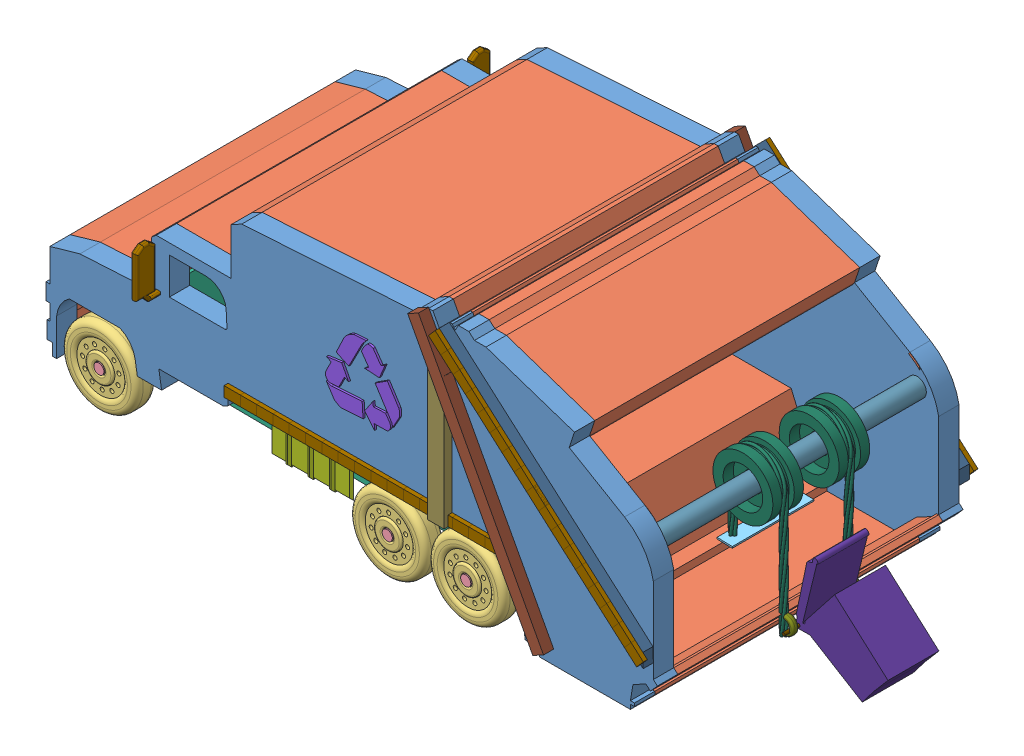
SolidWorks assembly Tech Fair Recycling Truck Final Assembly, configuration Default. Lengths in mm.
Overall size (91.31 33.89 44.17).
62 component instances, 31 part files, 112 mates.
Components (placement in the parent):
- Recycling Truck Side Panel-1: Recycling Truck Side Panel [Default] at (-47.2154 -27.4491 1.0648) size (76.2 30.73 2.54)
- Recycling Truck Side Panel-3: Recycling Truck Side Panel [Default] at (-47.2154 -27.4491 -34.4952) size (76.2 30.73 2.54)
- Part2^Tech Fair Recycling Truck Final Assembly-1: Part2^Tech Fair Recycling Truck Final Assembly [Default] at (-47.2154 -27.4491 1.0648) x (-1 0 0) z (0 0 -1) size (76.2 30.73 33.02) (virtual)
- Wheel-1: Wheel [Default] at (-36.0325 -11.6422 1.0648) x (0.936183 0.351512 0) z (0 0 1) size (9.53 9.53 2.54)
- Wheel-2: Wheel [Default] at (-36.0325 -11.6422 -34.4952) size (9.53 9.53 2.54)
- Front Wheel Axle-1: Front Wheel Axle [Default] at (-36.0325 -11.6422 -34.4952) size (1.27 1.27 38.1)
- Wheel Mounting Mechanism-3: Wheel Mounting Mechanism [Default] at (-41.5697 -12.5312 -14.1752) size (58.17 1.78 2.54)
- Front Wheel Axle-2: Front Wheel Axle [Default] at (-0.0915 -11.6422 -34.4952) x (0.996985 0.077595 0) z (0 0 1) size (1.27 1.27 38.1)
- Front Wheel Axle-3: Front Wheel Axle [Default] at (9.6875 -11.6422 -34.4952) x (-0.493037 -0.870008 0) z (0 0 1) size (1.27 1.27 38.1)
- Wheel-3: Wheel [Default] at (-0.0915 -11.6422 -34.4952) x (0.607478 -0.794336 0) z (0 0 1) size (9.53 9.53 2.54)
- Wheel-4: Wheel [Default] at (-0.0915 -11.6422 1.0648) x (0.999476 0.032368 0) z (0 0 1) size (9.53 9.53 2.54)
- Wheel-5: Wheel [Default] at (9.6875 -11.6422 -34.4952) x (-0.940272 -0.340425 0) z (0 0 1) size (9.53 9.53 2.54)
- Wheel-6: Wheel [Default] at (9.6875 -11.6422 1.0648) x (-0.248022 0.968754 0) z (0 0 1) size (9.53 9.53 2.54)
- Part Behind Wheels-1: Part Behind Wheels [Default] at (-20.0352 -6.4054 -1.7292) size (44.86 4.12 2.54)
- part on top of part behind wheels-1: part on top of part behind wheels [Default] at (-16.999 -12.5136 0.8108) size (10.16 5.08 0.76)
- Part Behind Wheels-2: Part Behind Wheels [Default] at (-19.9803 -6.4054 -31.7012) size (44.86 4.12 2.54)
- part on top of part behind wheels-4: part on top of part behind wheels [Default] at (-6.7184 -12.0011 -31.7012) x (-1 0 0) z (0 0 -1) size (10.16 5.08 0.76)
- Part3^Tech Fair Recycling Truck Final Assembly-1: Part3^Tech Fair Recycling Truck Final Assembly [Default] at origin (virtual)
- Part4^Tech Fair Recycling Truck Final Assembly-1: Part4^Tech Fair Recycling Truck Final Assembly [Default] at origin (virtual)
- Part6^Tech Fair Recycling Truck Final Assembly-1: Part6^Tech Fair Recycling Truck Final Assembly [Default] at origin (virtual)
- Recycyling Logo-1: Recycyling Logo [Default] at (-9.4381 -4.108 -34.7492) x (0.997898 0.064811 0) z (0 0 1) size (9.26 9.23 0.25)
- Recycyling Logo-2: Recycyling Logo [Default] at (-8.8451 -4.0695 3.6048) x (0.997898 0.064811 0) z (0 0 1) size (9.26 9.23 0.25)
- Color Part on top of side panel-1: Color Part on top of side panel [Default] at (-19.9264 -6.4054 3.6048) size (18.29 1.27 0.51)
- Color Part on top of side panel-2: Color Part on top of side panel [Default] at (-3.6704 -6.4054 3.6048) size (18.29 1.27 0.51)
- Color Part on top of side panel-3: Color Part on top of side panel [Default] at (-19.9264 -6.4054 -35.0032) size (18.29 1.27 0.51)
- Color Part on top of side panel-4: Color Part on top of side panel [Default] at (-3.6704 -6.4054 -35.0032) size (18.29 1.27 0.51)
- Side Part on Back-1: Side Part on Back [Default] at (6.8086 14.2643 3.6048) x (0.751135 -0.660149 0) z (0 0 1) size (36.83 1.27 1.27)
- Side Part on Back-2: Side Part on Back [Default] at (6.8698 14.334 -35.7652) x (0.751135 -0.660149 0) z (0 0 1) size (36.83 1.27 1.27)
- Color Part on top of side panel-5: Color Part on top of side panel [Default] at (6.819 14.2761 4.8748) x (0.751135 -0.660149 0) z (0 0 1) size (18.29 1.27 0.51)
- Color Part on top of side panel-6: Color Part on top of side panel [Default] at (19.0295 3.5448 4.8748) x (0.751135 -0.660149 0) z (0 0 1) size (18.29 1.27 0.51)
- Color Part on top of side panel-7: Color Part on top of side panel [Default] at (19.0803 3.6026 -36.2732) x (0.751135 -0.660149 0) z (0 0 1) size (18.29 1.27 0.51)
- Color Part on top of side panel-8: Color Part on top of side panel [Default] at (6.8698 14.334 -36.2732) x (0.751135 -0.660149 0) z (0 0 1) size (18.29 1.27 0.51)
- New Part-3: New Part [Default] at (3.7219 14.8477 3.6048) x (0.472165 -0.88151 0) z (0 0 1) size (33.02 1.52 1.27)
- Bar-1: Bar [Default] at (5.9675 10.1046 3.6048) size (2.03 16.51 1.02)
- New Part-2: New Part [Default] at (3.8237 14.7802 -35.7652) x (0.472165 -0.88151 0) z (0 0 1) size (33.02 1.52 1.27)
- Bar-2: Bar [Default] at (6.0879 10.1046 -35.5112) size (2.03 16.51 1.02)
- Gas Tank-1: Gas Tank [Default] at (-25.9449 -8.4074 -5.5392) size (15.24 6.76 7.62)
- Gas Tank-2: Gas Tank [Default] at (-25.9449 -8.4074 -17.7312) size (15.24 6.76 7.62)
- Part7^Tech Fair Recycling Truck Final Assembly-1: Part7^Tech Fair Recycling Truck Final Assembly [Default] at origin (virtual)
- Mount for Pulley-1: Mount for Pulley [Default] at (30.3925 1.8436 -31.9552) size (2.29 2.29 33.02)
- Pully-1: Pully [Default] at (42.0643 -12.8354 -24.9618) x (0 0 1) z (-0.999669 0.025718 0) size (3.81 18.98 8.49)
  - Pulley for Recycling-1: Pulley for Recycling [Default] at (4.5635 15.5704 12.0455) size (3.81 18.98 7.47)
  - Hook (2)-1: Hook (2) [Default] at (4.2001 1.6207 8.4944) x (0.000217 -0.999714 -0.023913) z (0.999915 0.000529 -0.013043) size (2.29 1.14 0.76)
- Pully-2: Pully [Default] at (42.438 -12.5303 -16.7068) x (0 0 1) z (-1 0 0) size (3.81 18.98 8.49)
  - Pulley for Recycling-1: Pulley for Recycling [Default] at (4.5635 15.5704 12.0455) size (3.81 18.98 7.47)
  - Hook (2)-1: Hook (2) [Default] at (4.2001 1.6207 8.4944) x (0.000217 -0.999714 -0.023913) z (0.999915 0.000529 -0.013043) size (2.29 1.14 0.76)
- Full Recycling Bin-1: Full Recycling Bin [Default] at (41.3657 -26.8748 -31.9551) x (0.609354 0.792898 0) z (0 0 1) size (8.24 12.7 10.16)
  - Recycling Bin-1: Recycling Bin [Default] at (3.4403 3.5074 12.5542) size (8.24 12.7 6.35)
  - Hook for trash can-1: Hook for trash can [Default] at (7.3321 14.2579 20.8092) x (0 0 -1) z (1 0 0) size (10.16 0.38 0.38)
- Headlights-1: Headlights [Default] at (-42.6199 -6.3502 -23.0651) x (0 0 -1) z (-1 0 0) size (6.35 2.54 0.8)
- Headlights-2: Headlights [Default] at (-42.6199 -8.8902 -7.9146) x (0 0 1) z (-1 0 0) size (6.35 2.54 0.8)
- grill-1: grill [Default] at (-43.7939 -11.0242 -20.8371) x (0 0 1) z (-1 0 0) size (10.67 7.11 1.02)
- Blinker Lights-1: Blinker Lights [Default] at (-42.3873 -4.6803 -26.4897) x (0 0 -1) z (-0.998811 -0.048757 0) size (3.3 1.02 0.25)
- Blinker Lights-2: Blinker Lights [Default] at (-42.2784 -4.6841 -4.2199) x (0 0 1) z (-1 0 0) size (3.3 1.02 0.25)
- Seat-1: Seat [Default] at (-27.1034 -7.6454 -5.1058) x (0 0 -1) z (1 0 0) size (7.62 10.16 6.35)
- Seat-2: Seat [Default] at (-25.9356 -7.6454 -17.9939) x (0 0 -1) z (1 0 0) size (7.62 10.16 6.35)
- Bracket for pulley-3: Bracket for pulley [Default] at (26.619 -5.6819 -10.7823) x (0 0 -1) z (-0.999669 0.025718 0) size (10.16 0.19 1.91)
- Steering Wheel Holder-1: Steering Wheel Holder [Default] at (-30.5969 -10.165 1.0648) x (0 0 -1) z (1 0 0) size (33.02 9.91 1.27)
- Steering Wheel-1: Steering Wheel [Default] at (-29.3269 -1.0275 -8.8154) x (0 0 -1) z (1 0 0) size (5.08 5.08 1.02)
- Closing Plate-1: Closing Plate [Default] at (-20.5245 -6.1514 1.0648) x (0 0 -1) z (1 0 0) size (33.02 12.19 1.27)
- Mirror-1: Mirror [Default] at (-28.2535 -12.3271 -26.894) x (0 0 1) z (-1 0 0) size (3.03 6.41 0.76)
- Mirror-2: Mirror [Default] at (-29.0155 -12.3271 -3.9965) x (0 0 -1) z (1 0 0) size (3.03 6.41 0.76)
Mates (geometry in assembly coordinates):
- Parallel6: parallel: line of Recycling Truck Side Panel-1 through (-19.5396 6.3589 3.6048) axis (0 1 0); line of Recycling Truck Side Panel-3 through (-19.5396 6.3589 -34.4952) axis (0 1 0)
- Parallel7: parallel: plane of Recycling Truck Side Panel-1 through (14.5181 -6.4054 3.6048) normal (0 -1 0); plane of Recycling Truck Side Panel-3 through (14.5181 -6.4054 -31.9552) normal (0 -1 0)
- Parallel8: parallel: plane of Recycling Truck Side Panel-1 through (-42.1489 -5.5248 3.6048) normal (-1 0 0); plane of Recycling Truck Side Panel-3 through (-29.7176 1.3715 -31.9552) normal (-1 0 0)
- Coincident4: coincident: plane of Recycling Truck Side Panel-1 through (-42.6199 -7.5722 3.6048) normal (-1 0 0); plane of Recycling Truck Side Panel-3 through (-42.6199 -7.5722 -31.9552) normal (-1 0 0)
- Coincident5: coincident: plane of Recycling Truck Side Panel-1 through (-42.1489 -1.4784 3.6048) normal (-0.274356 0.961628 0); plane of Recycling Truck Side Panel-3 through (-42.1489 -1.4784 -31.9552) normal (-0.274356 0.961628 0)
- Distance5: distance = 38.1 mm: line of Recycling Truck Side Panel-3 through (-42.1489 -5.5248 -34.4952) axis (0 1 0); line of Recycling Truck Side Panel-1 through (-42.1489 -5.5248 3.6048) axis (0 1 0)
- InPlace1: in place: plane of ? through (30.7442 2.1645 3.1314) normal (0 0 -1); plane of ? through (0 0 3.1314) normal (0 0 -1); moOrthogonalPlaneRef_w of ? through (30.7442 2.1645 3.1314) normal (0 0 -1); plane of ? through (0 0 3.1314) normal (0 1 0); plane of ? through (30.7442 2.1645 3.1314) normal (0 0 -1); plane of ? through (0 0 3.1314) normal (-1 0 0); plane of Recycling Truck Side Panel-1 through (25.6734 -1.3447 1.0648) normal (0 0 -1); unknown of Part2^Tech Fair Recycling Truck Final Assembly-1
- Coincident6: coincident aligned: plane of Recycling Truck Side Panel-1; plane of Part2^Tech Fair Recycling Truck Final Assembly-1
- Coincident7: coincident aligned: moOrthogonalPlaneRef_w of Recycling Truck Side Panel-1 through (-47.2154 -27.4491 1.0648) normal (0 1 0); plane of Part2^Tech Fair Recycling Truck Final Assembly-1 through (-47.2154 -27.4491 1.0648) normal (0 1 0)
- Coincident8: coincident anti-aligned: moOrthogonalPlaneRef_w of Recycling Truck Side Panel-1 through (-47.2154 -27.4491 1.0648) normal (1 0 0); plane of Part2^Tech Fair Recycling Truck Final Assembly-1 through (-47.2154 -27.4491 1.0648) normal (-1 0 0)
- Concentric1: concentric aligned: cylinder of Wheel-2 through (-36.0325 -11.6422 -31.9552) axis (0 0 -1) radius 0.635; cylinder of Front Wheel Axle-1 through (-36.0325 -11.6422 3.6048) axis (0 0 -1) radius 0.635
- Concentric2: concentric aligned: cylinder of Wheel-1 through (-36.0325 -11.6422 3.6048) axis (0 0 -1) radius 0.635; cylinder of Front Wheel Axle-1 through (-36.0325 -11.6422 3.6048) axis (0 0 -1) radius 0.635
- Coincident13: coincident aligned: plane of Recycling Truck Side Panel-3 through (25.6734 -1.3447 -34.4952) normal (0 0 -1); plane of Wheel-2 through (-36.0325 -11.6422 -34.4952) normal (0 0 -1)
- Distance6: distance = 17.78 mm: plane of Wheel Mounting Mechanism-3 through (16.5963 -12.5312 -14.1752) normal (0 0 1); plane of Recycling Truck Side Panel-3 through (25.6734 -1.3447 -31.9552) normal (0 0 1)
- Concentric4: concentric anti-aligned: cylinder of Front Wheel Axle-1 through (-36.0325 -11.6422 3.6048) axis (0 0 -1) radius 0.635; cylinder of Wheel Mounting Mechanism-3 through (-36.0325 -11.6422 -16.7152) axis (0 0 1) radius 0.635
- Coincident18: coincident: plane of Part2^Tech Fair Recycling Truck Final Assembly-1 through (-41.5697 -11.4298 -103.6886) normal (1 0 0); plane of Wheel Mounting Mechanism-3 through (-41.5697 -12.5312 -14.1752) normal (-1 0 0)
- Concentric5: concentric aligned: cylinder of Front Wheel Axle-3 through (9.6875 -11.6422 3.6048) axis (0 0 -1) radius 0.635; cylinder of Wheel-6 through (9.6875 -11.6422 3.6048) axis (0 0 -1) radius 0.635
- Concentric6: concentric aligned: cylinder of Front Wheel Axle-3 through (9.6875 -11.6422 3.6048) axis (0 0 -1) radius 0.635; cylinder of Wheel-5 through (9.6875 -11.6422 -31.9552) axis (0 0 -1) radius 0.635
- Concentric7: concentric aligned: cylinder of Front Wheel Axle-2 through (-0.0915 -11.6422 3.6048) axis (0 0 -1) radius 0.635; cylinder of Wheel-3 through (-0.0915 -11.6422 -31.9552) axis (0 0 -1) radius 0.635
- Concentric8: concentric aligned: cylinder of Front Wheel Axle-2 through (-0.0915 -11.6422 3.6048) axis (0 0 -1) radius 0.635; cylinder of Wheel-4 through (-0.0915 -11.6422 3.6048) axis (0 0 -1) radius 0.635
- Concentric9: concentric anti-aligned: cylinder of Wheel Mounting Mechanism-3 through (-0.0915 -11.6422 -16.7152) axis (0 0 1) radius 0.635; cylinder of Front Wheel Axle-2 through (-0.0915 -11.6422 3.6048) axis (0 0 -1) radius 0.635
- Concentric10: concentric anti-aligned: cylinder of Wheel Mounting Mechanism-3 through (9.6875 -11.6422 -16.7152) axis (0 0 1) radius 0.635; cylinder of Front Wheel Axle-3 through (9.6875 -11.6422 3.6048) axis (0 0 -1) radius 0.635
- Coincident23: coincident aligned: plane of Recycling Truck Side Panel-3 through (25.6734 -1.3447 -34.4952) normal (0 0 -1); plane of Wheel-3 through (-0.0915 -11.6422 -34.4952) normal (0 0 -1)
- Coincident24: coincident aligned: plane of Recycling Truck Side Panel-1 through (25.6734 -1.3447 3.6048) normal (0 0 1); plane of Wheel-6 through (9.6875 -11.6422 3.6048) normal (0 0 1)
- Coincident25: coincident aligned: plane of Recycling Truck Side Panel-3 through (25.6734 -1.3447 -34.4952) normal (0 0 -1); plane of Wheel-5 through (9.6875 -11.6422 -34.4952) normal (0 0 -1)
- Coincident26: coincident: plane of Part2^Tech Fair Recycling Truck Final Assembly-1 through (-41.5697 -11.4298 -103.6886) normal (1 0 0); line of Wheel Mounting Mechanism-3 through (-41.5697 -12.5312 -14.1752) axis (0 0 -1)
- Coincident28: coincident aligned: plane of Front Wheel Axle-3 through (9.6875 -11.6422 -34.4952) normal (0 0 -1); plane of Wheel-5 through (9.6875 -11.6422 -34.4952) normal (0 0 -1)
- Coincident29: coincident aligned: plane of Front Wheel Axle-2 through (-0.0915 -11.6422 -34.4952) normal (0 0 -1); plane of Wheel-3 through (-0.0915 -11.6422 -34.4952) normal (0 0 -1)
- Coincident30: coincident aligned: plane of Wheel-1 through (-36.0325 -11.6422 3.6048) normal (0 0 1); plane of Front Wheel Axle-1 through (-36.0325 -11.6422 3.6048) normal (0 0 1)
- Distance7: distance = 0.635 mm: line of Wheel Mounting Mechanism-3 through (-41.5697 -12.5312 -14.1752) axis (0 0 -1); line of Part2^Tech Fair Recycling Truck Final Assembly-1 through (-41.5697 -13.1662 -31.9552) axis (0 0 1)
- Coincident35: coincident: plane of Part2^Tech Fair Recycling Truck Final Assembly-1 through (14.5181 -6.4054 -103.6886) normal (0 -1 0); plane of Part Behind Wheels-1 through (-20.0352 -6.4054 0.8108) normal (0 1 0)
- Distance10: distance = 0.254 mm: line of Part Behind Wheels-1 through (14.5088 -6.4054 0.8108) axis (-1 0 0); line of Part2^Tech Fair Recycling Truck Final Assembly-1 through (14.5181 -6.4054 1.0648) axis (-1 0 0)
- Coincident42: coincident anti-aligned: plane of Part Behind Wheels-1 through (-20.0352 -6.4054 0.8108) normal (0 0 1); plane of part on top of part behind wheels-1 through (-16.999 -12.5136 0.8108) normal (0 0 -1)
- Distance11: distance = 2.9274 mm: line of part on top of part behind wheels-1 through (-16.999 -12.5136 1.0648) axis (0 1 0); line of Part2^Tech Fair Recycling Truck Final Assembly-1 through (-19.9264 -6.4054 1.0648) axis (0 -1 0)
- Distance14: distance = 0.254 mm: plane of Part Behind Wheels-2 through (-19.9803 -6.4054 -31.7012) normal (0 0 -1); line of Part2^Tech Fair Recycling Truck Final Assembly-1 through (14.5181 -6.4054 -31.9552) axis (-1 0 0)
- Coincident49: coincident: plane of Part2^Tech Fair Recycling Truck Final Assembly-1 through (14.5181 -6.4054 -103.6886) normal (0 -1 0); plane of Part Behind Wheels-2 through (-19.9803 -6.4054 -29.1612) normal (0 1 0)
- Coincident51: coincident anti-aligned: plane of Part Behind Wheels-2 through (-19.9803 -6.4054 -31.7012) normal (0 0 -1); plane of part on top of part behind wheels-4 through (-6.7184 -12.0011 -31.7012) normal (0 0 1)
- Distance16: distance = 3.048 mm: line of part on top of part behind wheels-4 through (-16.8784 -6.9211 -31.9552) axis (0 -1 0); line of Part2^Tech Fair Recycling Truck Final Assembly-1 through (-19.9264 -6.4054 -31.9552) axis (0 -1 0)
- Coincident53: coincident anti-aligned: plane of Recycling Truck Side Panel-3 through (25.6734 -1.3447 -34.4952) normal (0 0 -1); plane of Recycyling Logo-1 through (-4.1758 3.9824 -34.4952) normal (0 0 1)
- Coincident54: coincident anti-aligned: plane of Recycling Truck Side Panel-1 through (25.6734 -1.3447 3.6048) normal (0 0 1); plane of Recycyling Logo-2 through (-3.1097 5.7619 3.6048) normal (0 0 -1)
- Distance19: distance = 5.588 mm: line of Recycyling Logo-2 through (-2.4483 8.3149 3.8588) axis (-0.997898 -0.064811 0); line of Recycling Truck Side Panel-1 through (-18.2347 12.8836 3.6048) axis (0.997898 0.064811 0)
- Distance21: distance = 5.588 mm: line of Recycyling Logo-1 through (-3.0413 8.2764 -34.7492) axis (-0.997898 -0.064811 0); line of Recycling Truck Side Panel-3 through (-18.2347 12.8836 -34.4952) axis (0.997898 0.064811 0)
- Coincident55: coincident: point of Recycling Truck Side Panel-1; line of Color Part on top of side panel-1 through (-19.9264 -6.4054 4.1128) axis (0 0 -1)
- Coincident56: coincident: line of Recycling Truck Side Panel-1 through (-19.9264 -6.4054 3.6048) axis (0 -1 0); plane of Color Part on top of side panel-1 through (-19.9264 -5.1354 4.1128) normal (-1 0 0)
- Coincident57: coincident anti-aligned: plane of Recycling Truck Side Panel-1 through (25.6734 -1.3447 3.6048) normal (0 0 1); plane of Color Part on top of side panel-1 through (-11.7984 -5.1354 3.6048) normal (0 0 -1)
- Coincident58: coincident anti-aligned: plane of Recycling Truck Side Panel-1 through (25.6734 -1.3447 3.6048) normal (0 0 1); plane of Color Part on top of side panel-2 through (0.3936 -5.1354 3.6048) normal (0 0 -1)
- Coincident59: coincident anti-aligned: plane of Color Part on top of side panel-1 through (-3.6704 -6.4054 3.6048) normal (1 0 0); plane of Color Part on top of side panel-2 through (-3.6704 -5.1354 4.1128) normal (-1 0 0)
- Coincident60: coincident aligned: plane of Color Part on top of side panel-1 through (-3.6704 -5.1354 4.1128) normal (0 1 0); plane of Color Part on top of side panel-2 through (-3.6704 -5.1354 4.1128) normal (0 1 0)
- Coincident61: coincident aligned: line of Recycling Truck Side Panel-3 through (-19.9264 -6.4054 -34.4952) axis (0 -1 0); line of Color Part on top of side panel-3 through (-19.9264 -5.1354 -34.4952) axis (0 -1 0)
- Coincident62: coincident anti-aligned: line of Recycling Truck Side Panel-3 through (14.5181 -6.4054 -34.4952) axis (-1 0 0); line of Color Part on top of side panel-3 through (-19.9264 -6.4054 -34.4952) axis (1 0 0)
- Coincident63: coincident anti-aligned: line of Color Part on top of side panel-3 through (-3.6704 -5.1354 -35.0032) axis (0 0 1); line of Color Part on top of side panel-4 through (-3.6704 -5.1354 -34.4952) axis (0 0 -1)
- Coincident64: coincident aligned: line of Recycling Truck Side Panel-3 through (14.5181 -6.4054 -34.4952) axis (-1 0 0); line of Color Part on top of side panel-4 through (0.3936 -6.4054 -34.4952) axis (-1 0 0)
- Coincident65: coincident anti-aligned: line of Recycling Truck Side Panel-1 through (33.5801 -11.0649 3.6048) axis (-0.660149 -0.751135 0); line of Side Part on Back-1 through (34.4729 -10.049 3.6048) axis (0.660149 0.751135 0)
- Coincident66: coincident anti-aligned: plane of Recycling Truck Side Panel-1 through (25.6734 -1.3447 3.6048) normal (0 0 1); plane of Side Part on Back-1 through (6.8086 14.2643 3.6048) normal (0 0 -1)
- Coincident72: coincident anti-aligned: line of Recycling Truck Side Panel-3 through (33.5801 -11.0649 -34.4952) axis (-0.660149 -0.751135 0); line of Side Part on Back-2 through (34.5341 -9.9793 -34.4952) axis (0.660149 0.751135 0)
- Coincident73: coincident anti-aligned: plane of Recycling Truck Side Panel-3 through (25.6734 -1.3447 -34.4952) normal (0 0 -1); plane of Side Part on Back-2 through (6.8698 14.334 -34.4952) normal (0 0 1)
- Coincident74: coincident anti-aligned: plane of Side Part on Back-1 through (6.8086 14.2643 4.8748) normal (0 0 1); plane of Color Part on top of side panel-5 through (16.8152 7.1815 4.8748) normal (0 0 -1)
- Coincident75: coincident aligned: line of Side Part on Back-1 through (7.647 15.2182 4.8748) axis (-0.660149 -0.751135 0); line of Color Part on top of side panel-5 through (7.6574 15.2301 4.8748) axis (-0.660149 -0.751135 0)
- Coincident77: coincident anti-aligned: plane of Side Part on Back-1 through (6.8086 14.2643 4.8748) normal (0 0 1); plane of Color Part on top of side panel-6 through (29.0257 -3.5498 4.8748) normal (0 0 -1)
- Coincident78: coincident aligned: line of Color Part on top of side panel-5 through (19.8678 4.4987 5.3828) axis (-0.660149 -0.751135 0); line of Color Part on top of side panel-6 through (19.8678 4.4987 5.3828) axis (-0.660149 -0.751135 0)
- Coincident79: coincident aligned: plane of Color Part on top of side panel-5 through (20.5558 2.2033 5.3828) normal (-0.660149 -0.751135 0); plane of Color Part on top of side panel-6 through (22.0821 0.8619 5.3828) normal (-0.660149 -0.751135 0)
- Coincident80: coincident aligned: line of Side Part on Back-2 through (7.7082 15.2879 -35.7652) axis (-0.660149 -0.751135 0); line of Color Part on top of side panel-8 through (7.7082 15.2879 -35.7652) axis (-0.660149 -0.751135 0)
- Coincident81: coincident anti-aligned: plane of Side Part on Back-2 through (6.8698 14.334 -35.7652) normal (0 0 -1); plane of Color Part on top of side panel-8 through (16.8661 7.2394 -35.7652) normal (0 0 1)
- Coincident82: coincident aligned: plane of Side Part on Back-2 through (6.8698 14.334 -34.4952) normal (-0.660149 -0.751135 0); plane of Color Part on top of side panel-8 through (20.6066 2.2612 -35.7652) normal (-0.660149 -0.751135 0)
- Coincident85: coincident aligned: plane of Side Part on Back-2 through (6.8698 14.334 -34.4952) normal (-0.660149 -0.751135 0); plane of Color Part on top of side panel-7 through (19.0803 3.6026 -35.7652) normal (-0.660149 -0.751135 0)
- Coincident88: coincident anti-aligned: line of Color Part on top of side panel-7 through (19.9187 4.5565 -36.2732) axis (-0.660149 -0.751135 0); line of Color Part on top of side panel-8 through (19.0803 3.6026 -36.2732) axis (0.660149 0.751135 0)
- Coincident89: coincident aligned: plane of Side Part on Back-2 through (6.8698 14.334 -34.4952) normal (-0.660149 -0.751135 0); plane of Color Part on top of side panel-7 through (26.7118 -3.1045 -35.7652) normal (-0.660149 -0.751135 0)
- Coincident91: coincident anti-aligned: plane of Recycling Truck Side Panel-1 through (25.6734 -1.3447 3.6048) normal (0 0 1); plane of Im gay nigga-1 through (3.7219 14.8477 3.6048) normal (0 0 -1)
- Coincident93: coincident anti-aligned: plane of Recycling Truck Side Panel-1 through (25.6734 -1.3447 3.6048) normal (0 0 1); plane of please save my soul-1 through (5.9675 10.1046 3.6048) normal (0 0 -1)
- Coincident94: coincident anti-aligned: line of Recycling Truck Side Panel-1 through (14.5181 -6.4054 3.6048) axis (-1 0 0); line of please save my soul-1 through (5.9675 -6.4054 3.6048) axis (1 0 0)
- Coincident95: coincident anti-aligned: line of Recycling Truck Side Panel-3 through (3.9264 14.8352 -34.4952) axis (0.88151 0.472165 0); line of Im gay nigga-2 through (5.1671 15.4998 -34.4952) axis (-0.88151 -0.472165 0)
- Coincident96: coincident anti-aligned: plane of Recycling Truck Side Panel-3 through (25.6734 -1.3447 -34.4952) normal (0 0 -1); plane of Im gay nigga-2 through (3.8237 14.7802 -34.4952) normal (0 0 1)
- Coincident97: coincident anti-aligned: plane of Recycling Truck Side Panel-3 through (25.6734 -1.3447 -34.4952) normal (0 0 -1); plane of please save my soul-2 through (6.0879 10.1046 -34.4952) normal (0 0 1)
- Coincident98: coincident anti-aligned: line of Recycling Truck Side Panel-3 through (14.5181 -6.4054 -34.4952) axis (-1 0 0); line of please save my soul-2 through (6.0879 -6.4054 -34.4952) axis (1 0 0)
- Coincident100: coincident anti-aligned: plane of Part2^Tech Fair Recycling Truck Final Assembly-1 through (-20.5372 -7.8994 -103.6886) normal (0 -1 0); plane of gas gas gas i love gas-1 through (-25.9449 -7.8994 -5.5392) normal (0 1 0)
- Coincident101: coincident anti-aligned: plane of Part2^Tech Fair Recycling Truck Final Assembly-1 through (-20.5372 -7.8994 -103.6886) normal (0 -1 0); plane of gas gas gas i love gas-2 through (-25.9449 -7.8994 -17.7312) normal (0 1 0)
- Distance22: distance = 3.81 mm: line of gas gas gas i love gas-1 through (-25.9449 -8.4074 -5.5392) axis (1 0 0); line of Part Behind Wheels-1 through (-28.2348 -10.1161 -1.7292) axis (0.999957 -0.009305 0)
- Distance23: distance = 3.81 mm: line of gas gas gas i love gas-2 through (-15.7849 -8.4074 -25.3512) axis (-1 0 0); line of Part Behind Wheels-2 through (-28.1799 -10.1161 -29.1612) axis (0.999957 -0.009305 0)
- Distance24: distance = 2.794 mm: line of gas gas gas i love gas-1 through (-25.9449 -8.4074 -8.7819) axis (0 0 1); line of Part2^Tech Fair Recycling Truck Final Assembly-1 through (-28.2154 -10.0356 -31.9552) axis (0 0 1)
- Parallel10: parallel aligned: line of gas gas gas i love gas-1 through (-25.9449 -8.4074 -13.1592) axis (0 0 1); line of gas gas gas i love gas-2 through (-25.9449 -8.4074 -25.3512) axis (0 0 1)
- Distance25: distance = 2.794 mm: line of gas gas gas i love gas-2 through (-25.9449 -8.4074 -25.3512) axis (0 0 1); line of Part2^Tech Fair Recycling Truck Final Assembly-1 through (-28.2154 -10.0356 -31.9552) axis (0 0 1)
- Coincident104: coincident: plane of Recycling Truck Side Panel-1 through (25.6734 -1.3447 1.0648) normal (0 0 -1); plane of Mount for Pulley-1 through (30.3925 1.8436 1.0648) normal (0 0 1)
- Concentric18: concentric anti-aligned: cylinder of Mount for Pulley-1 through (30.3925 1.8436 1.0648) axis (0 0 -1) radius 1.143; cylinder of Pullys for nigga wippin-1/Pulley for Recycling-1 through (30.3925 1.8436 -20.3982) axis (0 0 1) radius 1.1965
- Distance32: distance = 9.652 mm anti-aligned: plane of Pullys for nigga wippin-1/Pulley for Recycling-1 through (30.456 4.3093 -22.3032) normal (0 0 -1); plane of Recycling Truck Side Panel-3 through (25.6734 -1.3447 -31.9552) normal (0 0 1)
- Concentric19: concentric anti-aligned: cylinder of Mount for Pulley-1 through (30.3925 1.8436 1.0648) axis (0 0 -1) radius 1.143; cylinder of Pullys for nigga wippin-2/Pulley for Recycling-1 through (30.3925 1.8436 -12.1432) axis (0 0 1) radius 2.4665
- Distance33: distance = 4.445 mm anti-aligned: plane of Pullys for nigga wippin-1/Pulley for Recycling-1 through (30.456 4.3093 -18.4932) normal (0 0 1); plane of Pullys for nigga wippin-2/Pulley for Recycling-1 through (30.3925 4.3101 -14.0482) normal (0 0 -1)
- Distance34: distance = 2.6416 mm: line of Headlights-1 through (-42.8739 -6.3502 -29.4151) axis (0 -1 0); line of Part2^Tech Fair Recycling Truck Final Assembly-1 through (-42.1489 -9.551 -31.9552) axis (0 1 0)
- Distance35: distance = 0.8636 mm: line of Headlights-1 through (-42.8739 -6.3502 -23.0651) axis (0 0 -1); line of Part2^Tech Fair Recycling Truck Final Assembly-1 through (-42.6199 -5.5248 -31.9552) axis (0 0 1)
- Coincident106: coincident anti-aligned: plane of Part2^Tech Fair Recycling Truck Final Assembly-1 through (-42.6199 -5.5248 -103.6886) normal (-1 0 0); plane of Headlights-1 through (-42.6199 -6.3502 -23.0651) normal (1 0 0)
- Coincident107: coincident anti-aligned: plane of Part2^Tech Fair Recycling Truck Final Assembly-1 through (-42.6199 -5.5248 -103.6886) normal (-1 0 0); plane of Headlights-2 through (-42.6199 -8.8902 -7.9146) normal (1 0 0)
- Distance36: distance = 2.6416 mm: line of Headlights-2 through (-42.8739 -8.8902 -1.5646) axis (0 1 0); line of Part2^Tech Fair Recycling Truck Final Assembly-1 through (-42.6199 -7.5722 1.0648) axis (0 1 0)
- Distance37: distance = 0.8636 mm: line of Headlights-2 through (-42.8739 -6.3502 -1.5646) axis (0 0 -1); line of Part2^Tech Fair Recycling Truck Final Assembly-1 through (-42.6199 -5.5248 -31.9552) axis (0 0 1)
- Distance38: distance = 1.27 mm: line of Blinker Lights-1 through (-42.3625 -5.1877 -28.7757) axis (0 0 1); line of Headlights-1 through (-42.8739 -6.3502 -23.0651) axis (0 0 -1)
- Parallel13: parallel aligned: line of Part2^Tech Fair Recycling Truck Final Assembly-1 through (33.5801 -11.0649 -31.9552) axis (0 0 1); line of Bracket for pulley-3 through (28.5233 -5.7309 -20.9423) axis (0 0 1)
- Coincident108: coincident anti-aligned: plane of Pullys for nigga wippin-1/Pulley for Recycling-1 through (27.2765 -5.6988 -20.3982) normal (-0.025718 -0.999669 0); plane of Bracket for pulley-3 through (26.619 -5.6819 -10.7823) normal (0.025718 0.999669 0)
- Parallel14: parallel aligned: plane of Recycling Truck Side Panel-3 through (25.6734 -1.3447 -34.4952) normal (0 0 -1); plane of Full Recycling Bin-1/Hook for trash can-1 through (34.5284 -12.3731 -21.3059) normal (0 0 -1)
- Coincident109: coincident anti-aligned: plane of Part2^Tech Fair Recycling Truck Final Assembly-1 through (-29.7176 -0.259 -103.6886) normal (0 -1 0); plane of Steering Wheel Holder-1 through (-29.3269 -0.259 1.0648) normal (0 1 0)
- Coincident110: coincident anti-aligned: plane of Recycling Truck Side Panel-1 through (25.6734 -1.3447 1.0648) normal (0 0 -1); plane of Steering Wheel Holder-1 through (-29.3269 -10.165 1.0648) normal (0 0 1)
- Coincident111: coincident anti-aligned: plane of Steering Wheel Holder-1 through (-29.3269 -10.165 1.0648) normal (1 0 0); plane of Steering Wheel-1 through (-29.3269 -1.0275 -8.8154) normal (-1 0 0)
- Coincident112: coincident: plane of Part2^Tech Fair Recycling Truck Final Assembly-1 through (14.6855 -6.1514 -103.6886) normal (0 1 0); plane of Closing Plate-1 through (-19.2545 -6.1514 1.0648) normal (0 -1 0)
- Coincident113: coincident: plane of Recycling Truck Side Panel-1 through (25.6734 -1.3447 1.0648) normal (0 0 -1); plane of Closing Plate-1 through (-19.2545 -6.1514 1.0648) normal (0 0 1)
- Distance39: distance = 6.35 mm: line of Seat-2 through (-20.8556 -7.6454 -25.6139) axis (0 1 0); line of Closing Plate-1 through (-20.5245 -6.1514 -31.9552) axis (0 1 0)
- Distance40: distance = 6.35 mm: line of Seat-1 through (-22.0234 2.5146 -5.1058) axis (0 -1 0); line of Closing Plate-1 through (-20.5245 6.0406 1.0648) axis (0 -1 0)
- Coincident114: coincident: plane of Recycling Truck Side Panel-3 through (25.6734 -1.3447 -34.4952) normal (0 0 -1); plane of Mirror-1 through (-50.8531 13.536 -34.4952) normal (0 0 1)
- Coincident115: coincident anti-aligned: plane of Recycling Truck Side Panel-3 through (25.6734 -1.3447 -34.4952) normal (0 0 -1); plane of Mirror-1 through (-29.0155 0.1888 -34.4952) normal (0 0 1)
- Parallel16: parallel aligned: plane of Seat-2 through (-20.8556 -7.6454 -17.9939) normal (-1 0 0); plane of Mirror-1 through (-29.0155 -12.3271 -26.894) normal (-1 0 0)
- Distance41: distance = 1.143 mm: line of Mirror-1 through (-29.0155 1.1616 -35.3971) axis (0 1 0); line of Recycling Truck Side Panel-3 through (-29.7176 -0.005 -34.4952) axis (0 1 0)
- Distance42: distance = 6.35 mm: line of Mirror-1 through (-29.0155 6.345 -36.0395) axis (0 0 -1); line of Recycling Truck Side Panel-3 through (-31.2379 -0.005 -34.4952) axis (1 0 0)
- Coincident116: coincident anti-aligned: plane of Recycling Truck Side Panel-1 through (25.6734 -1.3447 3.6048) normal (0 0 1); plane of Mirror-2 through (-28.2535 0.1888 3.6048) normal (0 0 -1)
- Parallel17: parallel aligned: plane of Seat-1 through (-22.0234 -7.6454 -5.1058) normal (-1 0 0); plane of Mirror-2 through (-29.0155 -12.3271 -3.9965) normal (-1 0 0)
- Distance43: distance = 1.143 mm: line of Mirror-2 through (-29.0155 5.8609 4.5067) axis (0 -1 0); line of Recycling Truck Side Panel-1 through (-29.7176 -0.005 3.6048) axis (0 1 0)
- Distance44: distance = 6.35 mm: line of Mirror-2 through (-29.0155 6.345 5.7411) axis (0 0 -1); line of Recycling Truck Side Panel-1 through (-31.2379 -0.005 3.6048) axis (1 0 0)
